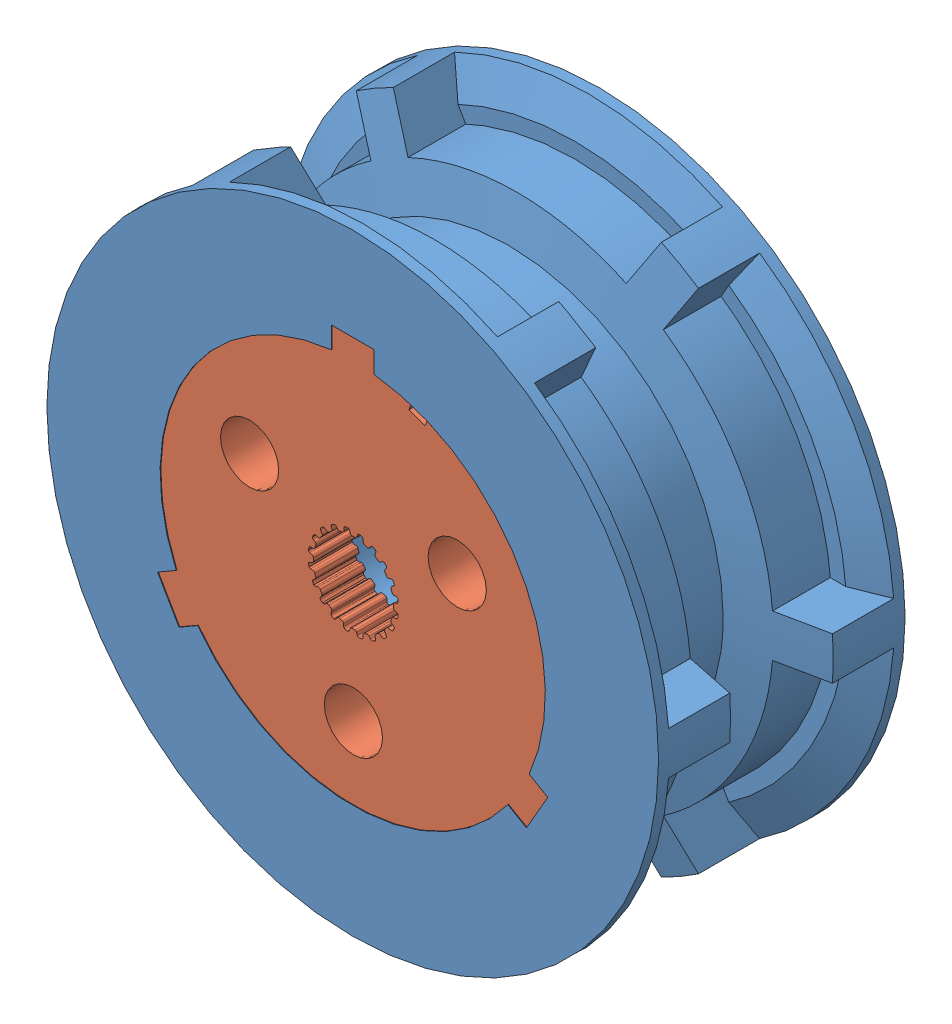
SolidWorks assembly DriveWheel, configuration Default. Lengths in mm.
Overall size (45.38 45.43 18.29).
3 component instances, 2 part files, 6 mates.
Components (placement in the parent):
- Custom Axle Drive_LEGO UWheel_6x3-1: Custom Axle Drive_LEGO UWheel_6x3 [Default] at (6.0935 29.6872 36.6042) size (45.38 45.43 18.29)
- WheelPlates w-Custom Axle-1: WheelPlates w-Custom Axle [Default] at (6.0935 29.6872 42.497) x (-1 0 0) z (0 0 1) size (28.95 30.08 3.2)
- WheelPlates w-Custom Axle-2: WheelPlates w-Custom Axle [Default] at (6.0935 29.6872 27.511) x (-1 0 0) z (0 0 1) size (28.95 30.08 3.2)
Mates (geometry in assembly coordinates):
- Coincident1: coincident: plane of Custom Axle Drive_LEGO UWheel_6x3-1 through (6.0935 29.6872 42.497) normal (0 0 1); plane of WheelPlates w-Custom Axle-1 through (6.0935 29.6872 42.497) normal (0 0 -1)
- Concentric1: concentric: cylinder of Custom Axle Drive_LEGO UWheel_6x3-1 through (6.0935 29.6872 45.7482) axis (0 0 -1) radius 4.064; cylinder of WheelPlates w-Custom Axle-1 through (6.0935 29.6872 45.6974) axis (0 0 -1) radius 14.2875
- Coincident2: coincident: plane of Custom Axle Drive_LEGO UWheel_6x3-1 through (6.0935 29.6872 30.7114) normal (0 0 -1); plane of WheelPlates w-Custom Axle-2 through (6.0935 29.6872 30.7114) normal (0 0 1)
- Concentric2: concentric: cylinder of Custom Axle Drive_LEGO UWheel_6x3-1 through (6.0935 29.6872 45.7482) axis (0 0 -1) radius 4.064; cylinder of WheelPlates w-Custom Axle-2 through (6.0935 29.6872 30.7114) axis (0 0 -1) radius 14.2875
- Coincident3: coincident: plane of Custom Axle Drive_LEGO UWheel_6x3-1 through (7.681 45.4826 42.497) normal (-1 0 0); plane of WheelPlates w-Custom Axle-1 through (7.681 45.4826 0.7495) normal (1 0 0)
- Coincident4: coincident: plane of Custom Axle Drive_LEGO UWheel_6x3-1 through (4.506 45.4826 30.7114) normal (1 0 0); plane of WheelPlates w-Custom Axle-2 through (4.506 45.4826 -14.2365) normal (-1 0 0)
